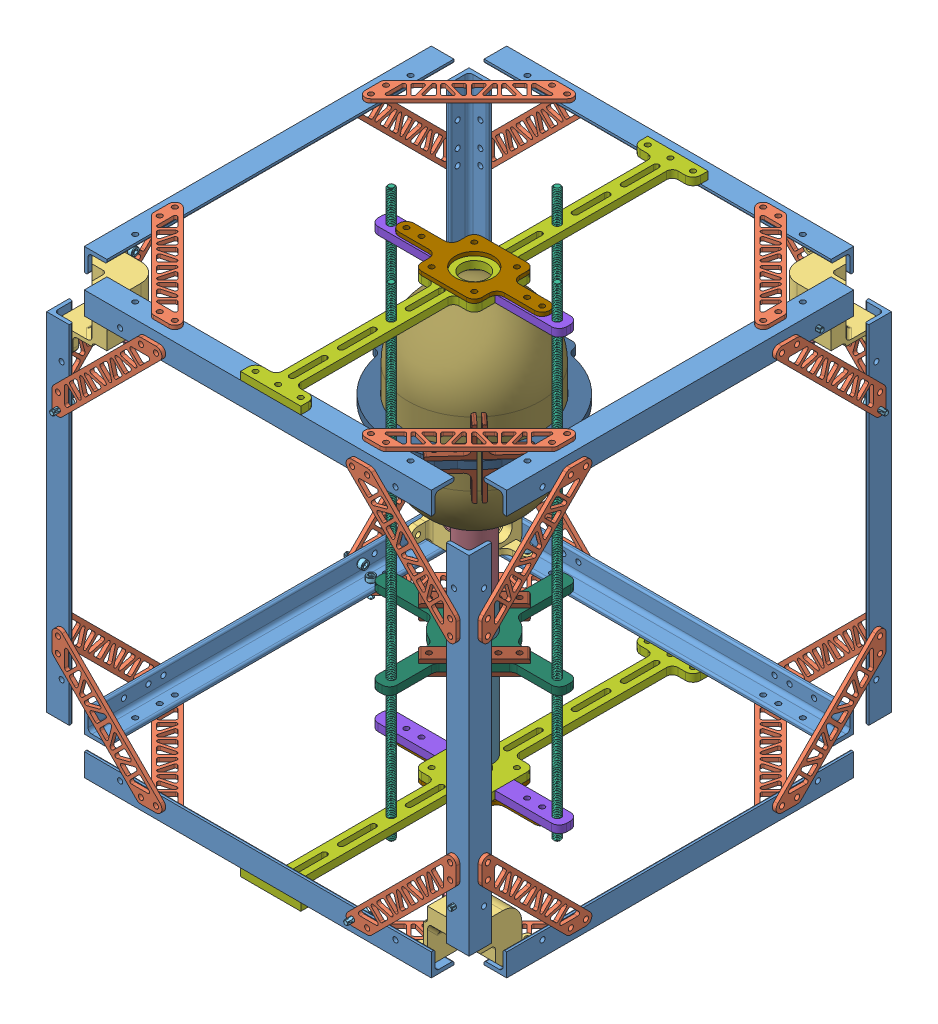
SolidWorks assembly FullCage_Struct, configuration Default. Lengths in mm.
Overall size (373.59 410.58 373.45).
116 component instances, 16 part files, 2 mates.
Components (placement in the parent):
- Better Structure Full Assembly-1: Better Structure Full Assembly [Default] at (0 14.8055 -9.0045) size (373.59 367.77 373.45)
  - Manifold+Bracket V3 Corner-1: Manifold+Bracket V3 Corner [Default] at (254.3502 283.8095 132.6396) size (332.84 327.03 332.71)
    - L_Bar-1: L_Bar [8982K281] at (15.875 28.575 152.4) x (0 1 0) z (0 0 1) size (19.05 19.05 292.1)
    - StrucBracket_Universal-1: StrucBracket_Universal [Default] at (-18.6648 41.275 18.6648) x (-0.707107 0 0.707107) z (0.707107 0 0.707107) size (19.05 3.17 126.81)
    - Thruster Block-1: Thruster Block [Default] at origin size (90.15 53.97 82.98)
      - Thruster Manifold-1: Thruster Manifold [Default] at origin size (63.5 53.97 63.5)
      - C15_212EP10FF_000-1: C15_212EP10FF_000 [Default] at (6.35 19.05 4.572) x (-0.955184 -0.296013 0) z (-0.296013 0.955184 0) size (15 56.18 15)
      - grainger-36x026-1: grainger-36x026 [Default] at (-9.525 3.3732 9.525) x (0 -1 0) z (0 0 1) size (18.47 12.77 12.72)
      - C15_212EP10FF_000-2: C15_212EP10FF_000 [Default] at (-4.572 19.05 -6.35) x (0 -0.16127 0.98691) z (0 -0.98691 -0.16127) size (15 56.18 15)
      - Generic_8-32-1: Generic_8-32 [91251A194] at (20.6306 25.4 36.5125) x (0 0.759298 -0.650742) z (-1 0 0) size (6.86 6.86 17.41)
    - L_Bar-2: L_Bar [8982K281] at (-152.4 28.575 -15.875) x (0 0 -1) z (-1 0 0) size (19.05 19.05 292.1)
    - StrucBracket_Universal-2: StrucBracket_Universal [Default] at (25.4 -5.9648 18.6648) x (0 -0.707107 0.707107) z (0 0.707107 0.707107) size (19.05 3.17 126.81)
    - StrucBracket_Universal-3: StrucBracket_Universal [Default] at (-18.6648 -5.9648 -28.575) x (-0.707107 -0.707107 0) z (-0.707107 0.707107 0) size (19.05 3.17 126.81)
    - L_Bar-3: L_Bar [8982K281] at (15.875 -139.7 -15.875) x (1 0 0) z (0 -1 0) size (19.05 19.05 292.1)
    - Generic_8-32-1: Generic_8-32 [91251A194] at (25.6267 -57.15 -12.7) x (0 0.486206 0.873844) z (-1 0 0) size (6.86 6.86 17.41)
    - Generic_8-32-2: Generic_8-32 [91251A194] at (12.7 -57.15 -25.4894) x (0.356037 0.934472 0) z (0 0 1) size (6.86 6.86 17.41)
  - Manifold+Bracket V3 Corner-2: Manifold+Bracket V3 Corner [Default] at (-50.4498 283.8095 437.4396) x (-1 0 0) z (0 0 -1) size (332.84 327.03 332.71)
    - L_Bar-1: L_Bar [8982K281] at (15.875 28.575 152.4) x (0 1 0) z (0 0 1) size (19.05 19.05 292.1)
    - StrucBracket_Universal-1: StrucBracket_Universal [Default] at (-18.6648 41.275 18.6648) x (-0.707107 0 0.707107) z (0.707107 0 0.707107) size (19.05 3.17 126.81)
    - Thruster Block-1: Thruster Block [Default] at origin size (90.15 53.97 82.98)
      - Thruster Manifold-1: Thruster Manifold [Default] at origin size (63.5 53.97 63.5)
      - C15_212EP10FF_000-1: C15_212EP10FF_000 [Default] at (6.35 19.05 4.572) x (-0.955184 -0.296013 0) z (-0.296013 0.955184 0) size (15 56.18 15)
      - grainger-36x026-1: grainger-36x026 [Default] at (-9.525 3.3732 9.525) x (0 -1 0) z (0 0 1) size (18.47 12.77 12.72)
      - C15_212EP10FF_000-2: C15_212EP10FF_000 [Default] at (-4.572 19.05 -6.35) x (0 -0.16127 0.98691) z (0 -0.98691 -0.16127) size (15 56.18 15)
      - Generic_8-32-1: Generic_8-32 [91251A194] at (20.6306 25.4 36.5125) x (0 0.759298 -0.650742) z (-1 0 0) size (6.86 6.86 17.41)
    - L_Bar-2: L_Bar [8982K281] at (-152.4 28.575 -15.875) x (0 0 -1) z (-1 0 0) size (19.05 19.05 292.1)
    - StrucBracket_Universal-2: StrucBracket_Universal [Default] at (25.4 -5.9648 18.6648) x (0 -0.707107 0.707107) z (0 0.707107 0.707107) size (19.05 3.17 126.81)
    - StrucBracket_Universal-3: StrucBracket_Universal [Default] at (-18.6648 -5.9648 -28.575) x (-0.707107 -0.707107 0) z (-0.707107 0.707107 0) size (19.05 3.17 126.81)
    - L_Bar-3: L_Bar [8982K281] at (15.875 -139.7 -15.875) x (1 0 0) z (0 -1 0) size (19.05 19.05 292.1)
    - Generic_8-32-1: Generic_8-32 [91251A194] at (25.6267 -57.15 -12.7) x (0 0.486206 0.873844) z (-1 0 0) size (6.86 6.86 17.41)
    - Generic_8-32-2: Generic_8-32 [91251A194] at (12.7 -57.15 -25.4894) x (0.356037 0.934472 0) z (0 0 1) size (6.86 6.86 17.41)
  - StrucBracket_Universal-1: StrucBracket_Universal [Default] at (235.6854 325.0845 418.7748) x (-0.707107 0 -0.707107) z (-0.707107 0 0.707107) size (19.05 3.17 126.81)
  - StrucBracket_Universal-2: StrucBracket_Universal [Default] at (-31.785 321.9095 151.3044) x (0.707107 0 0.707107) z (-0.707107 0 0.707107) size (19.05 3.17 126.81)
  - StrucBracket_Universal-3: StrucBracket_Universal [Default] at (-31.785 277.8447 107.2396) x (0.707107 -0.707107 0) z (0.707107 0.707107 0) size (19.05 3.17 126.81)
  - StrucBracket_Universal-4: StrucBracket_Universal [Default] at (235.6854 10.3743 104.0646) x (-0.707107 0.707107 0) z (0.707107 0.707107 0) size (19.05 3.17 126.81)
  - Manifold+Bracket V3 Corner-3: Manifold+Bracket V3 Corner [Default] at (-50.4498 -8.2905 145.3396) x (0 -1 0) z (1 0 0) size (332.84 327.03 332.71)
    - L_Bar-1: L_Bar [8982K281] at (15.875 28.575 152.4) x (0 1 0) z (0 0 1) size (19.05 19.05 292.1)
    - StrucBracket_Universal-1: StrucBracket_Universal [Default] at (-18.6648 41.275 18.6648) x (-0.707107 0 0.707107) z (0.707107 0 0.707107) size (19.05 3.17 126.81)
    - Thruster Block-1: Thruster Block [Default] at origin size (90.15 53.97 82.98)
      - Thruster Manifold-1: Thruster Manifold [Default] at origin size (63.5 53.97 63.5)
      - C15_212EP10FF_000-1: C15_212EP10FF_000 [Default] at (6.35 19.05 4.572) x (-0.955184 -0.296013 0) z (-0.296013 0.955184 0) size (15 56.18 15)
      - grainger-36x026-1: grainger-36x026 [Default] at (-9.525 3.3732 9.525) x (0 -1 0) z (0 0 1) size (18.47 12.77 12.72)
      - C15_212EP10FF_000-2: C15_212EP10FF_000 [Default] at (-4.572 19.05 -6.35) x (0 -0.16127 0.98691) z (0 -0.98691 -0.16127) size (15 56.18 15)
      - Generic_8-32-1: Generic_8-32 [91251A194] at (20.6306 25.4 36.5125) x (0 0.759298 -0.650742) z (-1 0 0) size (6.86 6.86 17.41)
    - L_Bar-2: L_Bar [8982K281] at (-152.4 28.575 -15.875) x (0 0 -1) z (-1 0 0) size (19.05 19.05 292.1)
    - StrucBracket_Universal-2: StrucBracket_Universal [Default] at (25.4 -5.9648 18.6648) x (0 -0.707107 0.707107) z (0 0.707107 0.707107) size (19.05 3.17 126.81)
    - StrucBracket_Universal-3: StrucBracket_Universal [Default] at (-18.6648 -5.9648 -28.575) x (-0.707107 -0.707107 0) z (-0.707107 0.707107 0) size (19.05 3.17 126.81)
    - L_Bar-3: L_Bar [8982K281] at (15.875 -139.7 -15.875) x (1 0 0) z (0 -1 0) size (19.05 19.05 292.1)
    - Generic_8-32-1: Generic_8-32 [91251A194] at (25.6267 -57.15 -12.7) x (0 0.486206 0.873844) z (-1 0 0) size (6.86 6.86 17.41)
    - Generic_8-32-2: Generic_8-32 [91251A194] at (12.7 -57.15 -25.4894) x (0.356037 0.934472 0) z (0 0 1) size (6.86 6.86 17.41)
  - StrucBracket_Universal-5: StrucBracket_Universal [Default] at (-79.0248 277.8447 151.3044) x (0 -0.707107 0.707107) z (0 0.707107 0.707107) size (19.05 3.17 126.81)
  - StrucBracket_Universal-6: StrucBracket_Universal [Default] at (235.6854 -33.6905 151.3044) x (-0.707107 0 0.707107) z (0.707107 0 0.707107) size (19.05 3.17 126.81)
  - StrucBracket_Universal-7: StrucBracket_Universal [Default] at (282.9252 277.8447 418.7748) x (0 -0.707107 -0.707107) z (0 0.707107 -0.707107) size (19.05 3.17 126.81)
  - StrucBracket_Universal-8: StrucBracket_Universal [Default] at (279.7502 10.3743 151.3044) x (0 0.707107 0.707107) z (0 0.707107 -0.707107) size (19.05 3.17 126.81)
  - Manifold+Bracket V3 Corner-4: Manifold+Bracket V3 Corner [Default] at (241.6502 -8.2905 437.4396) x (0 0 1) z (0 1 0) size (332.84 327.03 332.71)
    - L_Bar-1: L_Bar [8982K281] at (15.875 28.575 152.4) x (0 1 0) z (0 0 1) size (19.05 19.05 292.1)
    - StrucBracket_Universal-1: StrucBracket_Universal [Default] at (-18.6648 41.275 18.6648) x (-0.707107 0 0.707107) z (0.707107 0 0.707107) size (19.05 3.17 126.81)
    - Thruster Block-1: Thruster Block [Default] at origin size (90.15 53.97 82.98)
      - Thruster Manifold-1: Thruster Manifold [Default] at origin size (63.5 53.97 63.5)
      - C15_212EP10FF_000-1: C15_212EP10FF_000 [Default] at (6.35 19.05 4.572) x (-0.955184 -0.296013 0) z (-0.296013 0.955184 0) size (15 56.18 15)
      - grainger-36x026-1: grainger-36x026 [Default] at (-9.525 3.3732 9.525) x (0 -1 0) z (0 0 1) size (18.47 12.77 12.72)
      - C15_212EP10FF_000-2: C15_212EP10FF_000 [Default] at (-4.572 19.05 -6.35) x (0 -0.16127 0.98691) z (0 -0.98691 -0.16127) size (15 56.18 15)
      - Generic_8-32-1: Generic_8-32 [91251A194] at (20.6306 25.4 36.5125) x (0 0.759298 -0.650742) z (-1 0 0) size (6.86 6.86 17.41)
    - L_Bar-2: L_Bar [8982K281] at (-152.4 28.575 -15.875) x (0 0 -1) z (-1 0 0) size (19.05 19.05 292.1)
    - StrucBracket_Universal-2: StrucBracket_Universal [Default] at (25.4 -5.9648 18.6648) x (0 -0.707107 0.707107) z (0 0.707107 0.707107) size (19.05 3.17 126.81)
    - StrucBracket_Universal-3: StrucBracket_Universal [Default] at (-18.6648 -5.9648 -28.575) x (-0.707107 -0.707107 0) z (-0.707107 0.707107 0) size (19.05 3.17 126.81)
    - L_Bar-3: L_Bar [8982K281] at (15.875 -139.7 -15.875) x (1 0 0) z (0 -1 0) size (19.05 19.05 292.1)
    - Generic_8-32-1: Generic_8-32 [91251A194] at (25.6267 -57.15 -12.7) x (0 0.486206 0.873844) z (-1 0 0) size (6.86 6.86 17.41)
    - Generic_8-32-2: Generic_8-32 [91251A194] at (12.7 -57.15 -25.4894) x (0.356037 0.934472 0) z (0 0 1) size (6.86 6.86 17.41)
  - StrucBracket_Universal-9: StrucBracket_Universal [Default] at (-31.785 10.3743 462.8396) x (0.707107 0.707107 0) z (0.707107 -0.707107 0) size (19.05 3.17 126.81)
  - StrucBracket_Universal-10: StrucBracket_Universal [Default] at (-79.0248 10.3743 418.7748) x (0 0.707107 -0.707107) z (0 -0.707107 -0.707107) size (19.05 3.17 126.81)
  - StrucBracket_Universal-11: StrucBracket_Universal [Default] at (-31.785 -33.6905 418.7748) x (0.707107 0 -0.707107) z (-0.707107 0 -0.707107) size (19.05 3.17 126.81)
  - StrucBracket_Universal-12: StrucBracket_Universal [Default] at (235.6854 277.8447 466.0146) x (-0.707107 -0.707107 0) z (0.707107 -0.707107 0) size (19.05 3.17 126.81)
- FullCage-1: FullCage [Default] at (112.7426 336.715 282.3851) x (0 0 -1) z (-0.008727 -0.999962 0) size (342.9 209.34 408.77)
  - 98804A107_18-8 Stainless Steel Threaded Rod-1: 98804A107_18-8 Stainless Steel Threaded Rod [98804A107] at (0 -68.3672 170.2224) x (1 0 0) z (0 0.008727 0.999962) size (6.68 6.43 407.51)
  - Cage Lid-1: Cage Lid [Default] x (1 0 0) z (0 -0.008727 -0.999962) size (342.9 158.75 9.53)
    - Bearing_CrossBarHeavy-1: Bearing_CrossBarHeavy [Default] at origin size (342.9 50.8 6.35)
    - CrossBar_Extension-1: CrossBar_Extension [Default] at (0 52.3875 0) x (0 -1 0) z (-1 0 0) size (53.98 6.35 15.88)
    - CrossBar_Extension-2: CrossBar_Extension [Default] at (0 -52.3875 0) x (0 1 0) z (1 0 0) size (53.98 6.35 15.88)
    - CageBracket-1: CageBracket [Default] at (0 0 9.525) x (0 1 0) z (-1 0 0) size (127 3.17 50.8)
  - TankRing_Assy-1: TankRing_Assy [Default] at (0 0.7217 82.6939) x (0.73993 0.672659 -0.00587) z (0.672684 -0.739901 0.006457) size (180.05 57.15 180.38)
    - TankRing-1: TankRing [Default] x (0.73993 0 0.672684) z (-0.672684 0 0.73993) size (125.18 6.35 129.98)
    - TankRing_Bracket-1: TankRing_Bracket [8982K116] at (-17.4625 22.225 62.2074) size (31.75 25.4 12.7)
    - TankRing_Bracket-2: TankRing_Bracket [8982K116] at (-17.4625 22.225 -62.2074) size (31.75 25.4 12.7)
    - TankRing_Bracket-5: TankRing_Bracket [8982K116] at (-17.4625 -15.875 62.2074) x (1 0 0) z (0 0 -1) size (31.75 25.4 12.7)
    - TankRing_Bracket-6: TankRing_Bracket [8982K116] at (-17.4625 -15.875 -62.2074) x (1 0 0) z (0 0 -1) size (31.75 25.4 12.7)
  - 98804A107_18-8 Stainless Steel Threaded Rod-2: 98804A107_18-8 Stainless Steel Threaded Rod [98804A107] at (-69.85 1.4802 169.6128) x (0 -0.999962 0.008727) z (0 0.008727 0.999962) size (6.68 6.43 407.51)
  - 98804A107_18-8 Stainless Steel Threaded Rod-3: 98804A107_18-8 Stainless Steel Threaded Rod [98804A107] at (0 71.3275 169.0033) x (-1 0 0) z (0 0.008727 0.999962) size (6.68 6.43 407.51)
  - 98804A107_18-8 Stainless Steel Threaded Rod-4: 98804A107_18-8 Stainless Steel Threaded Rod [98804A107] at (69.85 1.4802 169.6128) x (0 0.999962 -0.008727) z (0 0.008727 0.999962) size (6.68 6.43 407.51)
  - TankRing_Assy-4: TankRing_Assy [Default] at (0 0.7217 82.6939) x (-0.73993 -0.672659 0.00587) z (-0.672684 0.739901 -0.006457) size (180.05 57.15 180.38)
    - TankRing-1: TankRing [Default] x (0.73993 0 0.672684) z (-0.672684 0 0.73993) size (125.18 6.35 129.98)
    - TankRing_Bracket-1: TankRing_Bracket [8982K116] at (-17.4625 22.225 62.2074) size (31.75 25.4 12.7)
    - TankRing_Bracket-2: TankRing_Bracket [8982K116] at (-17.4625 22.225 -62.2074) size (31.75 25.4 12.7)
    - TankRing_Bracket-5: TankRing_Bracket [8982K116] at (-17.4625 -15.875 62.2074) x (1 0 0) z (0 0 -1) size (31.75 25.4 12.7)
    - TankRing_Bracket-6: TankRing_Bracket [8982K116] at (-17.4625 -15.875 -62.2074) x (1 0 0) z (0 0 -1) size (31.75 25.4 12.7)
  - Cage Lid-2: Cage Lid [Default] at (0 3.1032 355.5865) x (1 0 0) z (0 0.008727 0.999962) size (342.9 158.75 9.53)
    - Bearing_CrossBarHeavy-1: Bearing_CrossBarHeavy [Default] at origin size (342.9 50.8 6.35)
    - CrossBar_Extension-1: CrossBar_Extension [Default] at (0 52.3875 0) x (0 -1 0) z (-1 0 0) size (53.98 6.35 15.88)
    - CrossBar_Extension-2: CrossBar_Extension [Default] at (0 -52.3875 0) x (0 1 0) z (1 0 0) size (53.98 6.35 15.88)
    - CageBracket-1: CageBracket [Default] at (0 0 9.525) x (0 1 0) z (-1 0 0) size (127 3.17 50.8)
  - LoFi Tank+Reg-1: LoFi Tank+Reg [Default] at (0 0.7659 87.769) x (-0.921374 -0.388662 0.003392) z (0 -0.008727 -0.999962) size (111.12 111.12 340.27)
    - LoFi Tank-1: LoFi Tank [Default] at origin size (111.12 111.12 163.23)
    - LoFi Reg 1-1: LoFi Reg 1 [Default] at (0 0 -80.6816) x (-0.38598 0.922507 0) z (-0.922507 -0.38598 0) size (28.57 57.15 28.57)
    - LoFi Reg 2-1: LoFi Reg 2 [Default] at (0 0 -137.8316) x (-0.99247 0.12249 0) z (-0.12249 -0.99247 0) size (30.16 119.89 30.16)
  - RegRing_Assy-1: RegRing_Assy [Default] at (0 2.28 261.2578) x (0.707107 0.70708 -0.006171) z (-0.707107 0.70708 -0.006171) size (145.48 57.15 145.48)
    - RegRing-1: RegRing [Default] x (0.707107 0 -0.707107) z (0.707107 0 0.707107) size (102.87 6.35 102.87)
    - TankRing_Bracket-1: TankRing_Bracket [8982K116] at (-17.4625 22.225 28.4622) size (31.75 25.4 12.7)
    - TankRing_Bracket-2: TankRing_Bracket [8982K116] at (-17.4625 -15.875 28.4622) x (1 0 0) z (0 0 -1) size (31.75 25.4 12.7)
    - TankRing_Bracket-3: TankRing_Bracket [8982K116] at (-17.4625 22.225 -28.4622) size (31.75 25.4 12.7)
    - TankRing_Bracket-4: TankRing_Bracket [8982K116] at (-17.4625 -15.875 -28.4622) x (1 0 0) z (0 0 -1) size (31.75 25.4 12.7)
  - RegRing_Assy-2: RegRing_Assy [Default] at (0 2.28 261.2578) x (-0.707107 -0.70708 0.006171) z (0.707107 -0.70708 0.006171) size (145.48 57.15 145.48)
    - RegRing-1: RegRing [Default] x (0.707107 0 -0.707107) z (0.707107 0 0.707107) size (102.87 6.35 102.87)
    - TankRing_Bracket-1: TankRing_Bracket [8982K116] at (-17.4625 22.225 28.4622) size (31.75 25.4 12.7)
    - TankRing_Bracket-2: TankRing_Bracket [8982K116] at (-17.4625 -15.875 28.4622) x (1 0 0) z (0 0 -1) size (31.75 25.4 12.7)
    - TankRing_Bracket-3: TankRing_Bracket [8982K116] at (-17.4625 22.225 -28.4622) size (31.75 25.4 12.7)
    - TankRing_Bracket-4: TankRing_Bracket [8982K116] at (-17.4625 -15.875 -28.4622) x (1 0 0) z (0 0 -1) size (31.75 25.4 12.7)
Mates (geometry in assembly coordinates):
- Coincident1: coincident anti-aligned: plane of Better Structure Full Assembly-1/Manifold+Bracket V3 Corner-4/L_Bar-2 through (279.7502 -18.885 129.9851) normal (0 -1 0); plane of FullCage-1/Cage Lid-2/Bearing_CrossBarHeavy-1 through (112.7426 -18.885 282.3851) normal (0 1 0)
- Coincident4: coincident aligned: plane of Better Structure Full Assembly-1/Manifold+Bracket V3 Corner-2/L_Bar-2 through (248.0002 336.715 453.8351) normal (0 0 1); plane of FullCage-1/Cage Lid-1/Bearing_CrossBarHeavy-1 through (112.7426 343.065 453.8351) normal (0 0 1)
